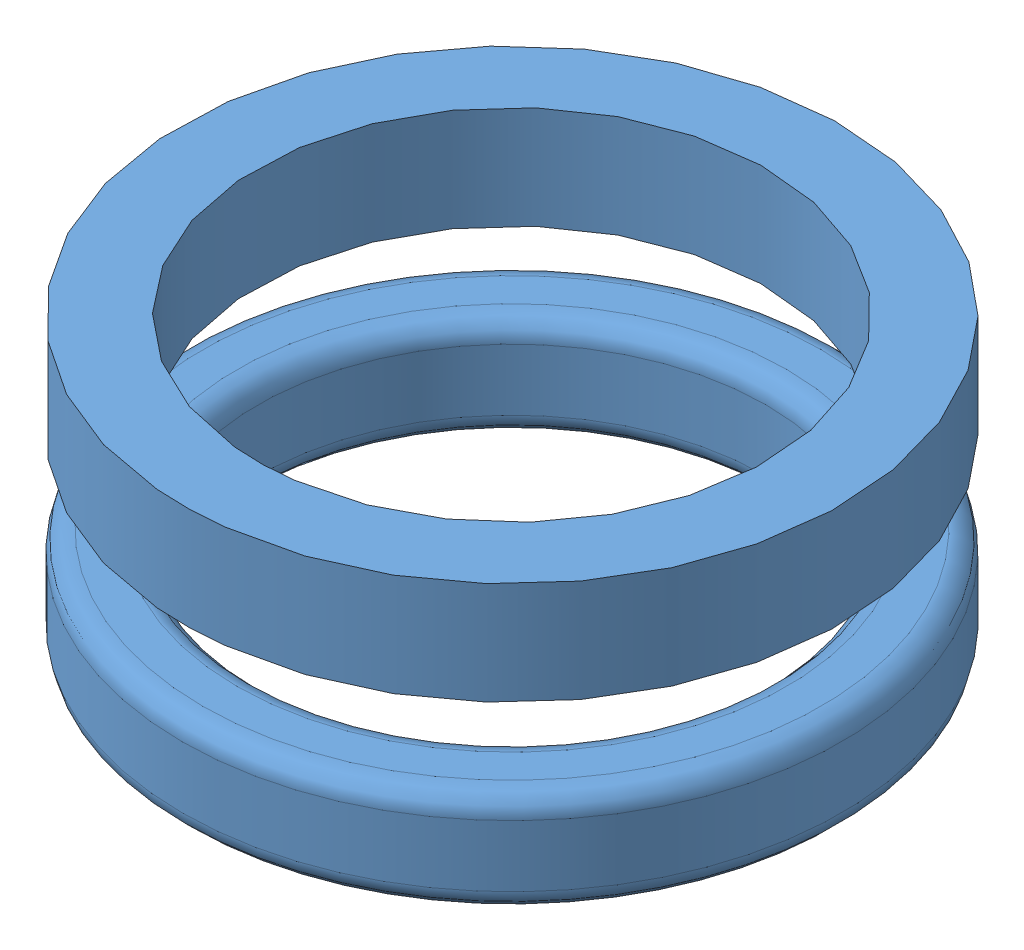
SolidWorks assembly two_circles, configuration two_circles_config1. Lengths in mm.
Overall size (65.59 27.98 65.59).
2 component instances, 1 part files, 1 mates.
Components (placement in the parent):
- circle-1: circle [Circle_Config1] at (-14.1587 7.4697 2.3965) size (64.24 10 64.24)
- circle-2: circle [Circle_Config2_nf] at (-14.1587 25.4501 2.3965) x (0.999776 0 -0.021142) z (0.021142 0 0.999776) size (64.24 10 64.24)
Mates (geometry in assembly coordinates):
- Concentric1: concentric aligned: cylinder of circle-1 through (-14.1587 17.4697 2.3965) axis (0 -1 0) radius 24.7757; cylinder of circle-2 through (-14.1587 35.4501 2.3965) axis (0 -1 0) radius 24.7757
